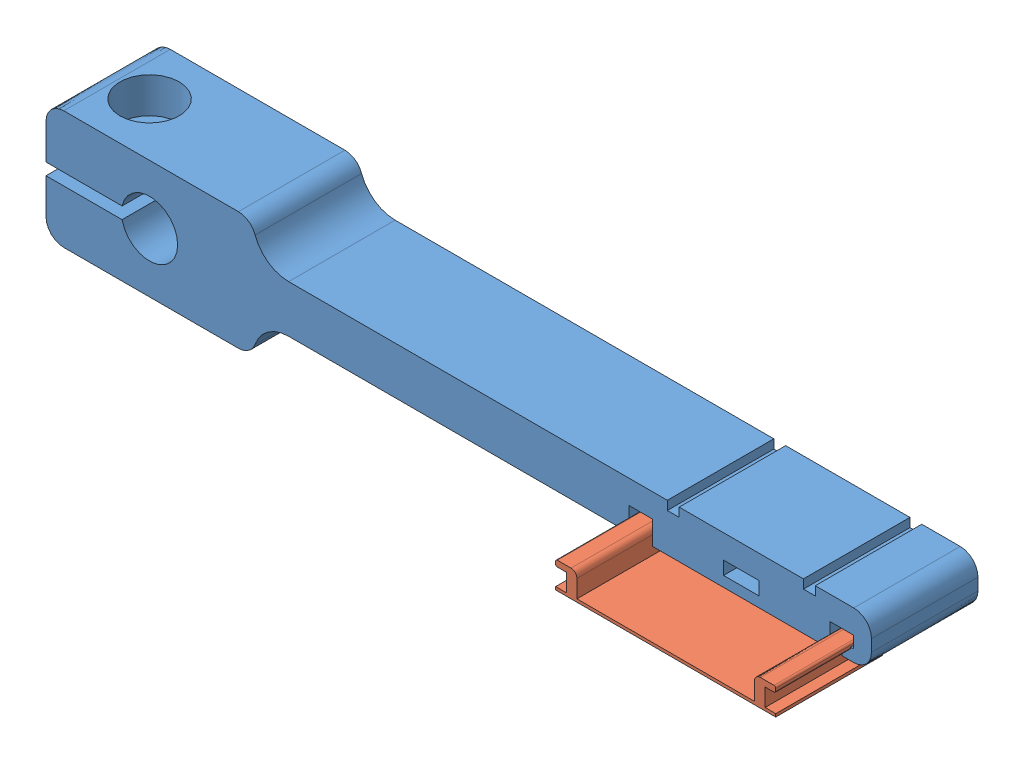
SolidWorks assembly beam+plate assembly, configuration Default. Lengths in mm.
Overall size (139.5 20 30.67).
2 component instances, 2 part files, 0 mates.
Components (placement in the parent):
- moment beam V3-1: moment beam V3 [Default] at (-51.5265 0.1068 -9.4544) size (139.5 20 18)
- finger presure plate-1: finger presure plate [Default] at (48.3606 -5.2933 3.2119) size (37.2 4.5 18)
